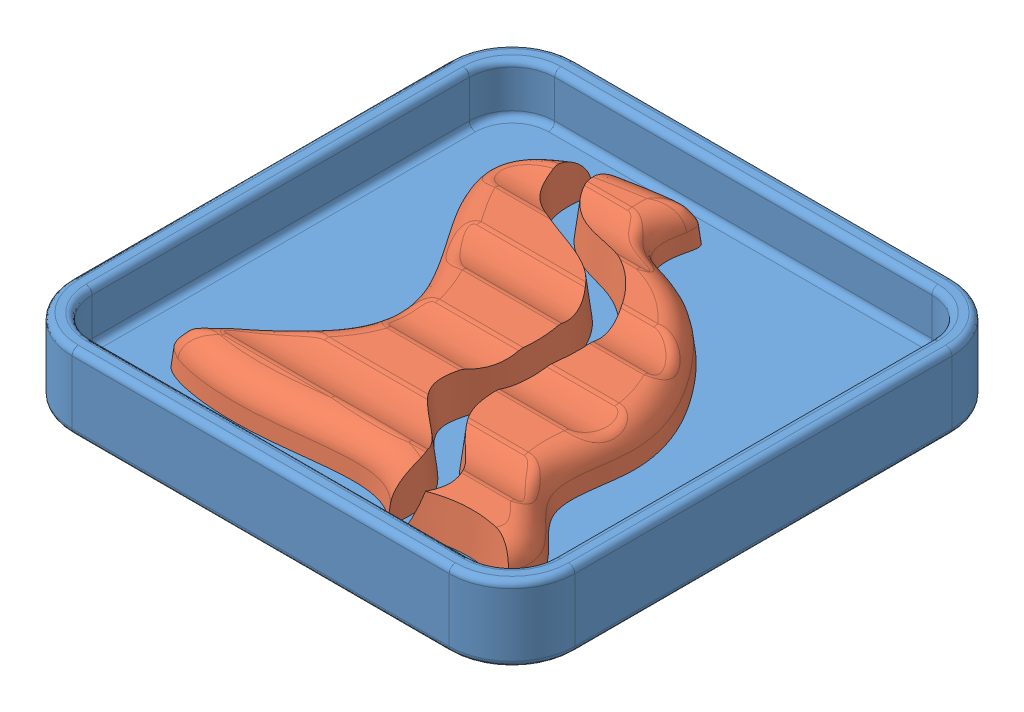
SolidWorks assembly Vortex2, configuration Default. Lengths in mm.
Overall size (40 6 40).
2 component instances, 2 part files, 2 mates.
Components (placement in the parent):
- Tile-1: Tile [Default] at (19.949 16.4937 28.9933) size (40 6 40)
- Vortex2-1: Vortex2 [Default] at (20.0761 18.4937 28.5933) size (35 3.59 35)
Mates (geometry in assembly coordinates):
- Coincident1: coincident anti-aligned: plane of Tile-1 through (4.949 18.4937 43.9933) normal (0 1 0); plane of Vortex2-1 through (22.1165 18.4937 27.3739) normal (0 -1 0)
- Coincident2: coincident anti-aligned: line of Tile-1 through (34.949 18.4937 11.0933) axis (-1 0 0); line of Vortex2-1 through (2.5761 18.4937 11.0933) axis (1 0 0)
